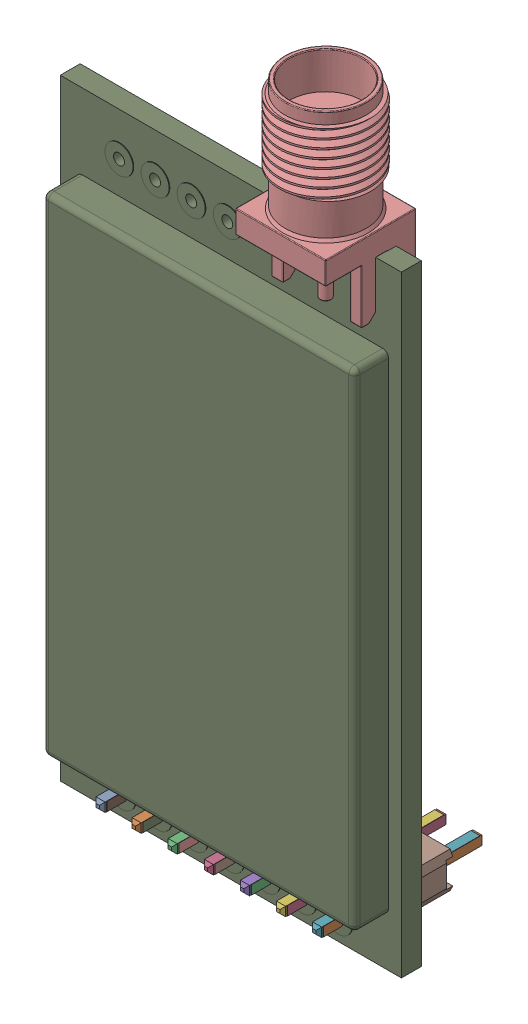
SolidWorks assembly LoRA_-_ES32, configuration Default. Lengths in mm.
Overall size (24 52.5 13.62).
15 component instances, 6 part files, 0 mates.
Components (placement in the parent):
- STEP-7pin-61300711121-rev1-1: STEP-7pin-61300711121-rev1 [Default] at (165.6081 105.664 1.2975) x (1 0 0) z (0 -1 0) size (17.78 11.54 2.54)
  - 6130xx11121_PIN-1: 6130xx11121_PIN [Default] at (-7.62 1.5 0) x (1 0 0) z (0 -1 0) size (0.64 0.64 11.54)
  - 6130xx11121_PIN-2: 6130xx11121_PIN [Default] at (-5.08 1.5 0) x (1 0 0) z (0 -1 0) size (0.64 0.64 11.54)
  - 6130xx11121_PIN-3: 6130xx11121_PIN [Default] at (-2.54 1.5 0) x (1 0 0) z (0 -1 0) size (0.64 0.64 11.54)
  - 6130xx11121_PIN-4: 6130xx11121_PIN [Default] at (0 1.5 0) x (1 0 0) z (0 -1 0) size (0.64 0.64 11.54)
  - 6130xx11121_PIN-5: 6130xx11121_PIN [Default] at (2.54 1.5 0) x (1 0 0) z (0 -1 0) size (0.64 0.64 11.54)
  - 6130xx11121_PIN-6: 6130xx11121_PIN [Default] at (5.08 1.5 0) x (1 0 0) z (0 -1 0) size (0.64 0.64 11.54)
  - 6130xx11121_PIN-7: 6130xx11121_PIN [Default] at (7.62 1.5 0) x (1 0 0) z (0 -1 0) size (0.64 0.64 11.54)
  - 61300711121-1: 61300711121 [Default] at origin size (17.78 2.54 2.54)
- E32-TTL-1: E32-TTL [Default] at (165.6386 192.5439 25.4) x (0 1 0) z (1 0 0) size (52.5 13.62 24)
  - E32-TTL-1W_Predeterminado-1: E32-TTL-1W_Predeterminado [Default] at (-66.873 -19.9517 0) size (43 3.79 24)
  - SMA_CONNECTOR_-_EMPCB.SMAFSTJ.B.HT-1: SMA_CONNECTOR_-_EMPCB.SMAFSTJ.B.HT [Default] at (-43.773 -15.0017 10.2201) x (0 0 1) z (1 0 0) size (6.58 6.47 13.3)
  - 05__HEADER-3WAY-1ROW-2.54MM-VERTICAL-PCB_Predeterminado-1: 05__HEADER-3WAY-1ROW-2.54MM-VERTICAL-PCB_Predeterminado [Default] at (-87.6961 -24.2405 2.52) x (0 -1 0) z (0 0 1) size (11.55 2.54 7.62)
  - 05__HEADER-3WAY-1ROW-2.54MM-VERTICAL-PCB_Predeterminado-2: 05__HEADER-3WAY-1ROW-2.54MM-VERTICAL-PCB_Predeterminado [Default] at (-87.6961 -24.2405 -5.1) x (0 -1 0) z (0 0 1) size (11.55 2.54 7.62)
  - HEADER-1WAY-1ROW-2.54MM-VERTICAL-PCB_Predeterminado-1: HEADER-1WAY-1ROW-2.54MM-VERTICAL-PCB_Predeterminado [Default] at (-86.893 -19.9517 -7.64) x (0 -1 0) z (-1 0 0) size (11.54 2.54 2.54)
